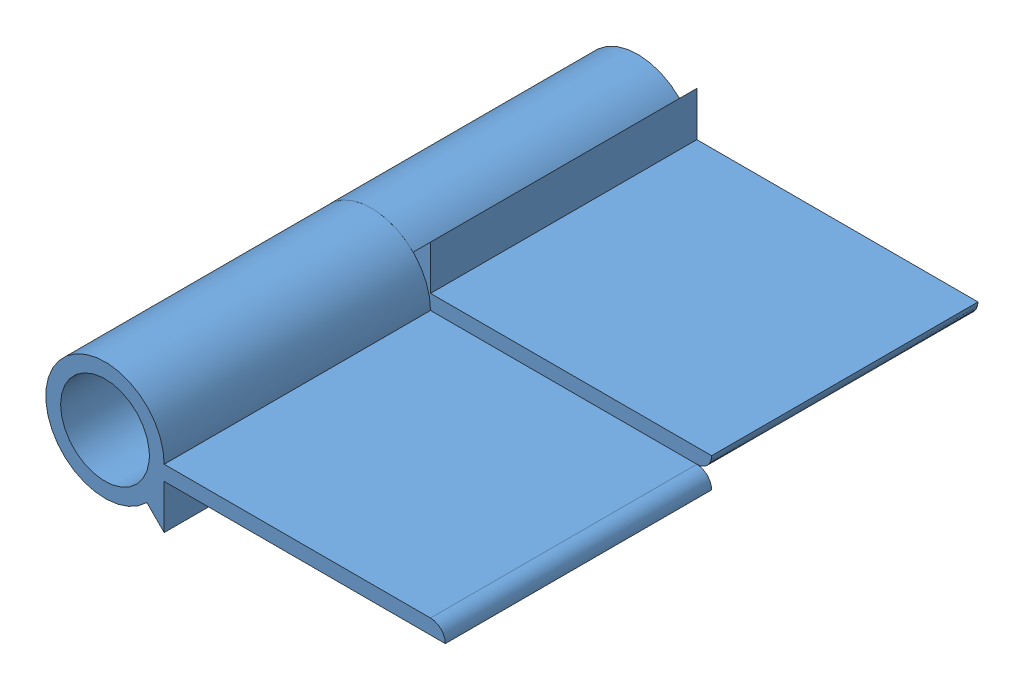
SolidWorks assembly Bisabra, configuration Default. Lengths in mm.
Overall size (54 16 72).
2 component instances, 1 part files, 1 mates.
Components (placement in the parent):
- Bisagra-1: Bisagra [Default] at (4.5212 31.9216 19.0662) size (54 16 36)
- Bisagra-2: Bisagra [Default] at (4.5212 31.9216 91.0662) x (1 0 0) z (0 0 -1) size (54 16 36)
Mates (geometry in assembly coordinates):
- Hinge1: hinge = 3.141593 rad anti-aligned: cylinder of Bisagra-2 through (4.5212 31.9216 55.0662) axis (0 0 1) radius 8; cylinder of Bisagra-1 through (4.5212 31.9216 55.0662) axis (0 0 -1) radius 8; plane of Bisagra-1 through (48.5212 33.9216 55.0662) normal (0 0 1); plane of Bisagra-2 through (48.5212 29.9216 55.0662) normal (0 0 -1); plane of Bisagra-2 through (50.5212 29.9216 55.0662) normal (0 -1 0); plane of Bisagra-1 through (50.5212 33.9216 55.0662) normal (0 1 0)
